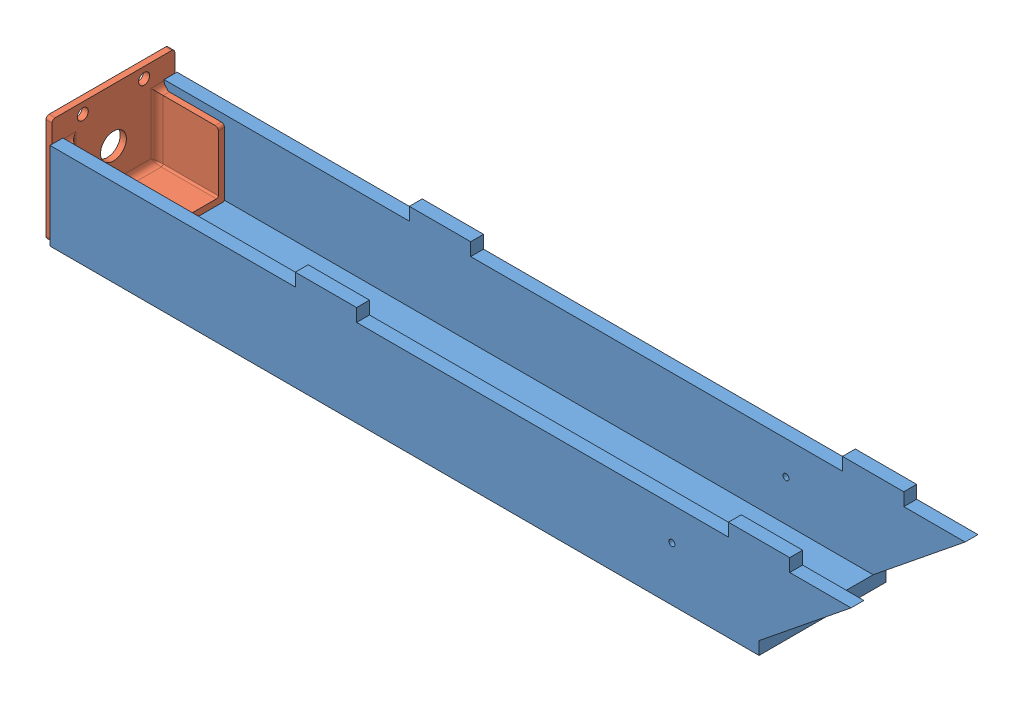
SolidWorks assembly Swappable Power Pod, configuration Default. Lengths in mm.
Overall size (334.33 44.96 52.58).
2 component instances, 2 part files, 3 mates.
Components (placement in the parent):
- Swappable Power Pod-1: Swappable Power Pod [Default] at origin size (331.79 41.45 52.58)
- 3D Printed Firewall-1: 3D Printed Firewall [Default] at (-149.3838 22.733 0) x (0 0 -1) z (0 -1 0) size (50.8 27.94 44.45)
Mates (geometry in assembly coordinates):
- Coincident1: coincident anti-aligned: plane of Swappable Power Pod-1 through (0 5.334 0) normal (0 1 0); plane of 3D Printed Firewall-1 through (-121.4438 5.334 19.812) normal (0 -1 0)
- Coincident3: coincident anti-aligned: plane of Swappable Power Pod-1 through (-146.8438 5.334 26.289) normal (-1 0 0); plane of 3D Printed Firewall-1 through (-146.8438 1.778 24.13) normal (1 0 0)
- Coincident6: coincident anti-aligned: plane of Swappable Power Pod-1 through (0 0 0) normal (0 0 1); plane of 3D Printed Firewall-1
